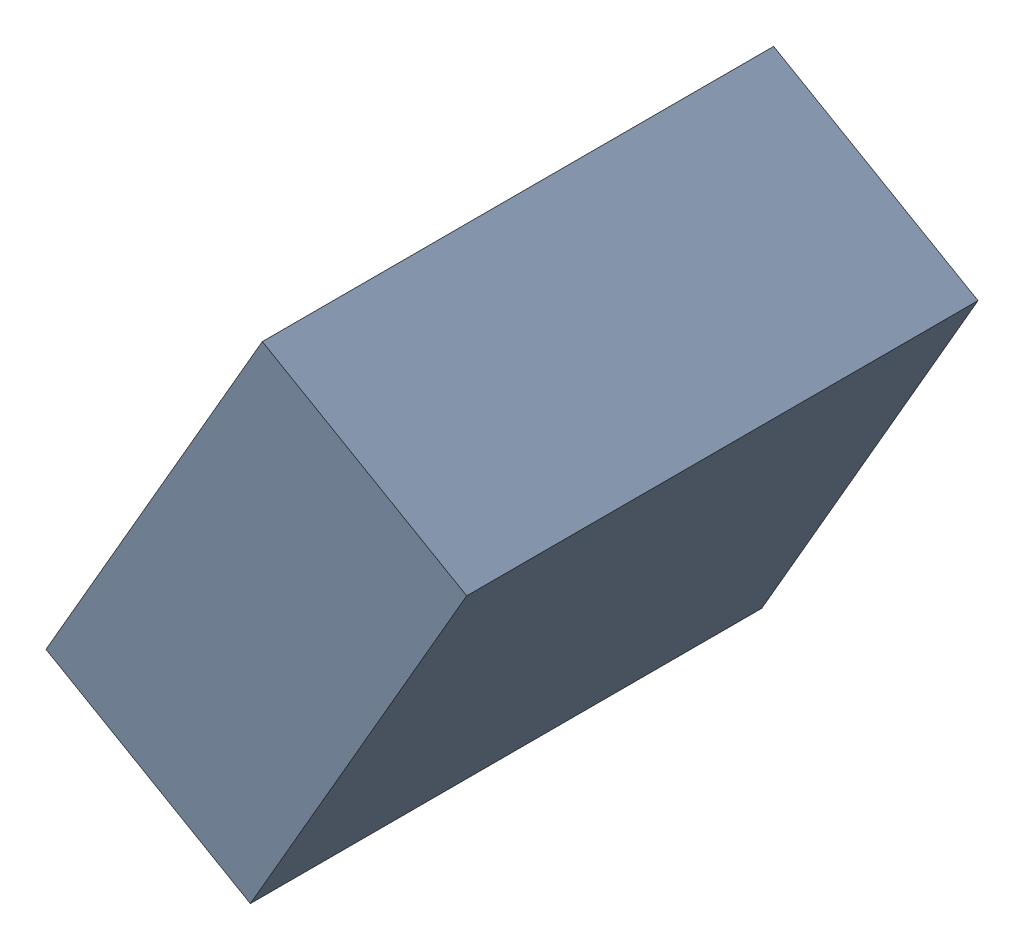
SolidWorks assembly C26_TDA6, configuration Standard. Lengths in mm.
Overall size (1.07 1.25 1.3).
2 component instances, 1 part files, 0 mates.
Components (placement in the parent):
- 885543328-1: 885543328 [Standard] at (-33.6621 21.6879 0) size (1.07 1.25 1.3)
  - Extruded_26-1: Extruded_26 [Standard] at origin size (1.07 1.25 1.3)
